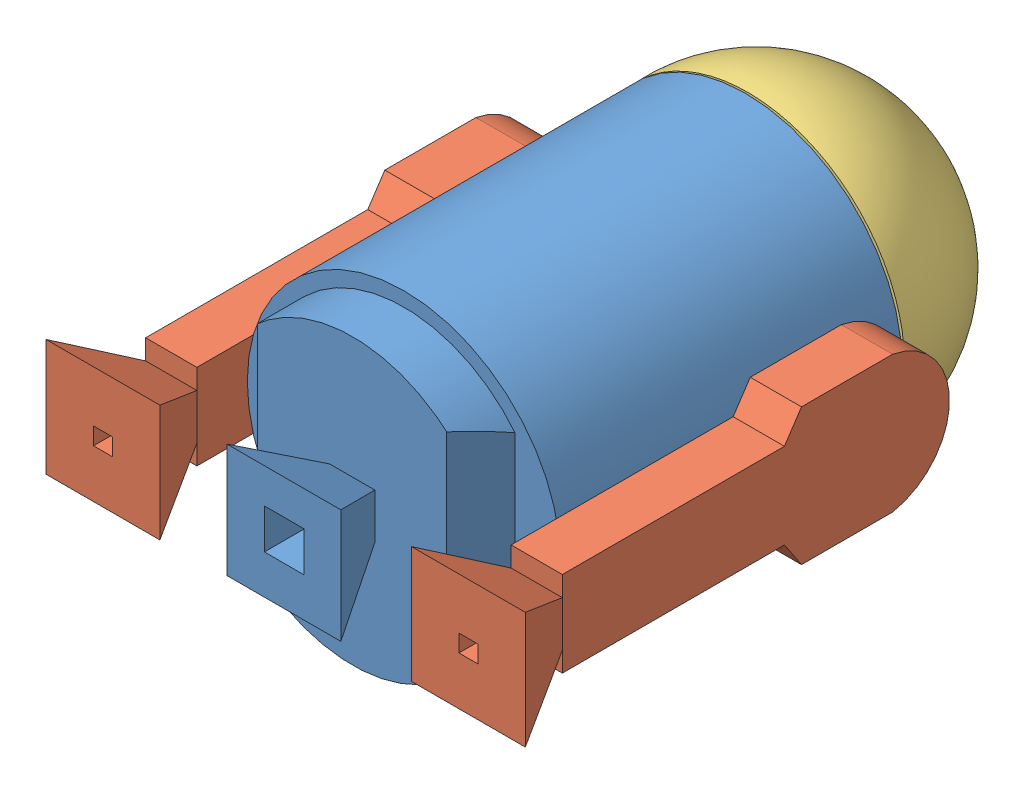
SolidWorks assembly R2-D2, configuration Valor predeterminado. Lengths in mm.
Overall size (84.46 55.2 110.25).
4 component instances, 3 part files, 0 mates.
Components (placement in the parent):
- Corpo-1: Corpo [Valor predeterminado] at (-17.116 1.0972 0) size (55 55 81)
- Braço-2: Braço [Valor predeterminado] at (15.2684 0.8845 12.0582) x (0 1 0) z (-1 0 0) size (24 79.99 20)
- Braço-3: Braço [Valor predeterminado] at (-49.1962 0.0159 11.7722) x (0 1 0) z (-1 0 0) size (24 79.99 20)
- Cabeça-1: Cabeça [Valor predeterminado] at (-16.8816 1.2666 -13.2591) x (-1 0 0) z (0 -1 0) size (55.07 29 55.07)
